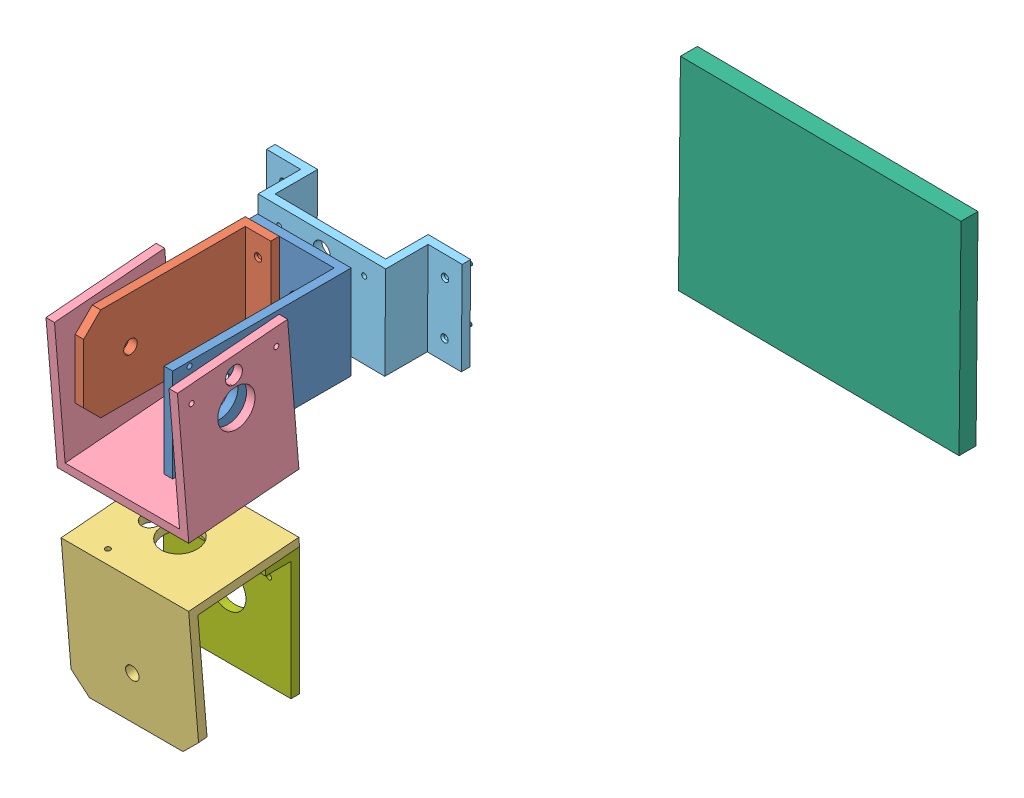
SolidWorks assembly Assem1, configuration Varsayılan. Lengths in mm.
Overall size (403.86 359.56 162.18).
7 component instances, 7 part files, 14 mates.
Components (placement in the parent):
- robot-kol-omuz-1.parcaa-1: robot-kol-omuz-1.parcaa [Varsayılan] at (6.8392 1.0943 52.5) size (55 55 105)
- robot-kol-omuz-2.parcaa-1: robot-kol-omuz-2.parcaa [Varsayılan] at (-22.9608 1.0943 107.5) size (20 55 100)
- robot-kol-omuz-dirsekk-1: robot-kol-omuz-dirsekk [Varsayılan] at (11.0086 -86.6637 129.4426) x (1 0 0) z (0 -0.083207 0.996532) size (75 80 65)
- robot-kol-omuz-kol-baglanti-11-1: robot-kol-omuz-kol-baglanti-11 [Varsayılan] at (39.3392 0.6782 134.9827) x (1 0 0) z (0 -0.083207 0.996532) size (77.3 80 65)
- robot-kol-sabit-1.parcaa-1: robot-kol-sabit-1.parcaa [Varsayılan] at (6.8392 1.0943 37.5) x (0.999954 -0.009624 0) z (0 0 1) size (115 55 30)
- robot-kol-sabit-yuzeyy-1: robot-kol-sabit-yuzeyy [Varsayılan] at (269.8684 132.4638 2.5) x (0.999954 -0.009624 0) z (0 0 1) size (392.95 210.59 10)
- robot-kol-omuz-dirsek-parca-22-1: robot-kol-omuz-dirsek-parca-22 [Varsayılan] at (9.1464 -128.9665 97.0553) size (75 75 20)
Mates (geometry in assembly coordinates):
- Çakışık1: coincident anti-aligned: plane of robot-kol-sabit-1.parcaa-1 through (6.8392 1.0943 12.5) normal (0 0 -1); plane of robot-kol-sabit-yuzeyy-1 through (269.8684 132.4638 12.5) normal (0 0 1)
- Eş Merkezli3: concentric aligned: circle of robot-kol-omuz-1.parcaa-1; circle of robot-kol-sabit-1.parcaa-1
- Eş Merkezli4: concentric aligned: circle of robot-kol-omuz-1.parcaa-1; circle of robot-kol-omuz-2.parcaa-1
- Eş Merkezli5: concentric aligned: circle of robot-kol-omuz-1.parcaa-1; circle of robot-kol-omuz-2.parcaa-1
- Eş Merkezli6: concentric anti-aligned: circle of robot-kol-omuz-1.parcaa-1; circle of robot-kol-omuz-2.parcaa-1
- Uzaklık1: distance = 10 mm anti-aligned: plane of robot-kol-sabit-1.parcaa-1 through (6.8392 1.0943 42.5) normal (0 0 1); plane of robot-kol-omuz-1.parcaa-1 through (6.8392 1.0943 52.5) normal (0 0 -1)
- Eş Merkezli7: concentric aligned: circle of robot-kol-omuz-1.parcaa-1; circle of robot-kol-omuz-kol-baglanti-11-1
- Uzaklık2: distance = 5 mm anti-aligned: plane of robot-kol-omuz-kol-baglanti-11-1 through (-27.9608 0.6782 134.9827) normal (1 0 0); plane of robot-kol-omuz-2.parcaa-1 through (-22.9608 1.0943 107.5) normal (-1 0 0)
- Uzaklık4: distance = 30 mm anti-aligned: plane of robot-kol-omuz-kol-baglanti-11-1 through (39.3392 -51.6397 130.6143) normal (0 -0.996532 -0.083207); plane of robot-kol-omuz-dirsekk-1 through (11.0086 -81.681 129.8586) normal (0 0.996532 0.083207)
- Çakışık7: coincident anti-aligned: line of robot-kol-omuz-dirsekk-1 through (-26.4914 -83.9594 97.0553) axis (1 0 0); line of robot-kol-omuz-dirsek-parca-22-1 through (48.5086 -83.9594 97.0553) axis (-1 0 0)
- Çakışık8: coincident: point of robot-kol-omuz-dirsekk-1; point of robot-kol-omuz-dirsek-parca-22-1
- Eş Merkezli8: concentric aligned: circle of robot-kol-sabit-1.parcaa-1; circle of robot-kol-sabit-yuzeyy-1
- Eş Merkezli9: concentric aligned: circle of robot-kol-sabit-1.parcaa-1; circle of robot-kol-sabit-yuzeyy-1
- Çakışık9: coincident anti-aligned: plane of robot-kol-sabit-1.parcaa-1 through (6.8392 1.0943 12.5) normal (0 0 -1); plane of robot-kol-sabit-yuzeyy-1 through (269.8684 132.4638 12.5) normal (0 0 1)
